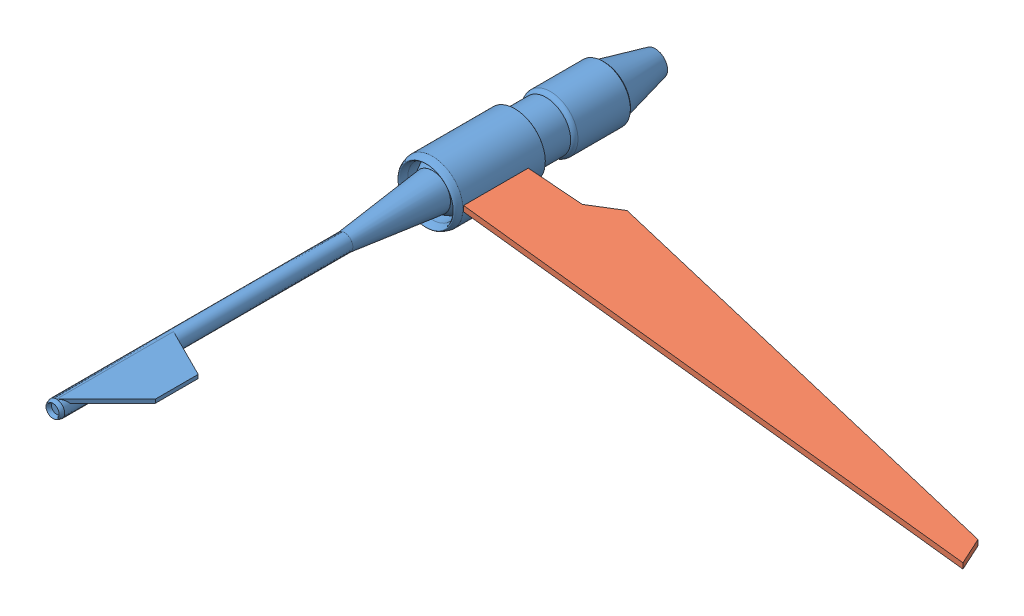
SolidWorks assembly Vector_Right_EngineandWing, configuration Default. Lengths in mm.
Overall size (8471.7 832.5 8230.5).
2 component instances, 2 part files, 1 mates.
Components (placement in the parent):
- Vector_Engine_Right-1: Vector_Engine_Right [Default] at origin size (1093.02 832.5 8230.5)
- Vector_Wing_Right-2: Vector_Wing_Right [Default] at (314.1355 -37.5 2.7052) size (7639.2 75 1873.8)
Mates (geometry in assembly coordinates):
- Tangent1: tangent anti-aligned: cylinder of Vector_Engine_Right-1 through (0 0 -1125) axis (0 0 1) radius 416.25; plane of Vector_Wing_Right-2 through (416.25 37.5 2.7052) normal (-1 0 0)
